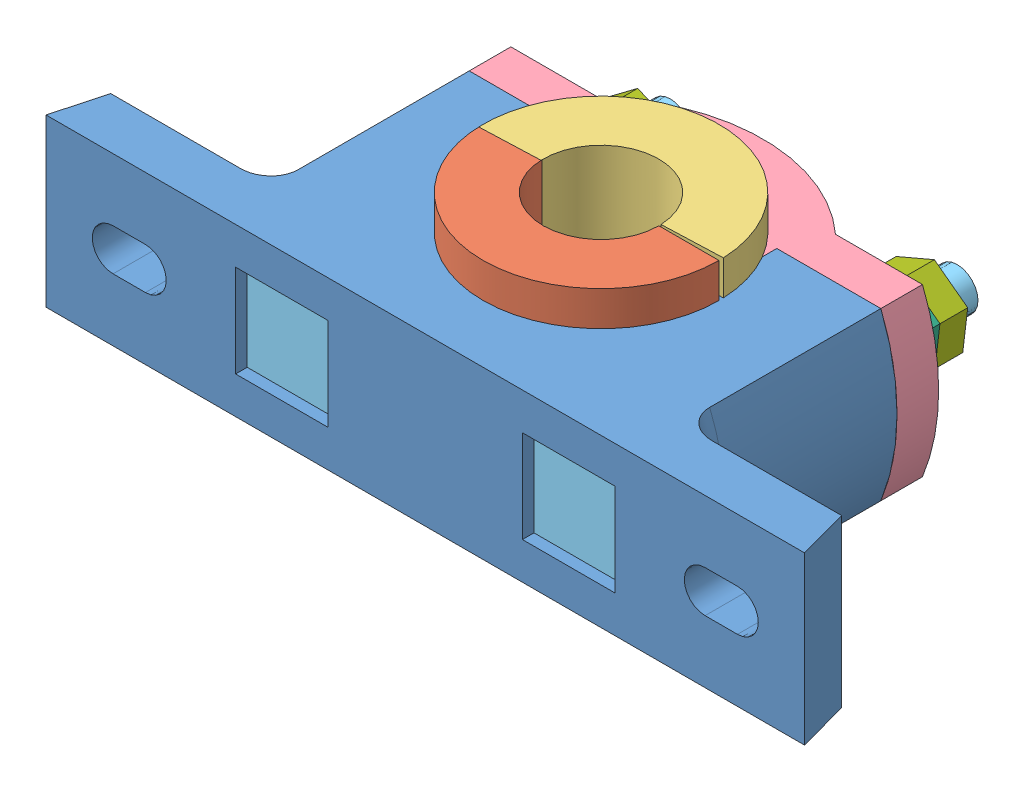
SolidWorks assembly Assem1, configuration Default. Lengths in mm.
Overall size (164 51 84).
10 component instances, 7 part files, 20 mates.
Components (placement in the parent):
- casting-1: casting [Default] at (-12.8779 141.074 -86.6135) size (164 36 54)
- brass lower-1: brass lower [Default] at (-12.8779 141.074 -124.6135) x (0 1 0) z (0 0 1) size (51 51 25.5)
- brass upper-1: brass upper [Default] at (-12.8779 141.074 -124.6135) x (0 1 0) z (-0.999278 0 0.037986) size (51 25.5 51)
- cap-1: cap [Default] at (-12.8779 141.074 -121.6135) size (96 36 32)
- bolt-1: bolt [Default] at (-43.8779 141.074 -94.6135) x (-1 0 0) z (0 0 1) size (19 19 82)
- nut-2: nut [Default] at (-43.8779 141.074 -158.6135) x (0.119049 -0.992888 0) z (0 0 1) size (18 15.59 9)
- lock nut-2: lock nut [Default] at (-43.8779 141.074 -164.6135) x (-0.800342 -0.599543 0) z (0 0 1) size (18 15.59 6)
- bolt-2: bolt [Default] at (18.1221 141.074 -94.6135) x (-1 0 0) z (0 0 1) size (19 19 82)
- lock nut-3: lock nut [Default] at (18.1221 141.074 -158.6135) x (0.800342 -0.599543 0) z (0 0 -1) size (18 15.59 6)
- nut-3: nut [Default] at (18.1221 141.074 -149.6135) x (-0.119049 -0.992888 0) z (0 0 -1) size (18 15.59 9)
Mates (geometry in assembly coordinates):
- Coincident2: coincident anti-aligned: cylinder of casting-1 through (-12.8779 141.074 -105.6135) axis (0 0 -1) radius 3; circle of brass lower-1
- Parallel1: parallel aligned: plane of casting-1 through (-12.8779 159.074 -124.6135) normal (0 1 0); plane of brass lower-1 through (-12.8779 166.574 -124.6135) normal (0 1 0)
- Concentric1: concentric aligned: cylinder of brass lower-1 through (-12.8779 115.574 -124.6135) axis (0 1 0) radius 12.5; cylinder of brass upper-1 through (-12.8779 115.574 -124.6135) axis (0 1 0) radius 12.5
- Concentric2: concentric aligned: cylinder of brass lower-1 through (-12.8779 115.574 -124.6135) axis (0 1 0) radius 12.5; cylinder of brass upper-1 through (-12.8779 115.574 -124.6135) axis (0 1 0) radius 12.5
- Coincident4: coincident aligned: plane of brass lower-1 through (-12.8779 166.574 -124.6135) normal (0 1 0); plane of brass upper-1 through (-12.8779 166.574 -124.6135) normal (0 1 0)
- Coincident5: coincident anti-aligned: circle of casting-1; cylinder of cap-1 through (18.1221 141.074 -127.6135) axis (0 0 -1) radius 4.5
- Coincident6: coincident anti-aligned: plane of casting-1 through (37.1221 159.074 -140.6135) normal (0 0 -1); plane of cap-1 through (9.1221 159.074 -140.6135) normal (0 0 1)
- Concentric4: concentric aligned: cylinder of casting-1 through (-43.8779 141.074 -140.6135) axis (0 0 1) radius 4.5; cylinder of bolt-1 through (-43.8779 141.074 -170.6135) axis (0 0 1) radius 4.5
- Parallel3: parallel aligned: plane of casting-1 through (-33.8779 151.074 -94.6135) normal (-1 0 0); plane of bolt-1 through (-53.3779 150.574 -88.6135) normal (-1 0 0)
- Parallel5: parallel aligned: plane of casting-1 through (-53.8779 151.074 -94.6135) normal (1 0 0); plane of bolt-1 through (-34.3779 150.574 -88.6135) normal (1 0 0)
- Coincident11: coincident anti-aligned: plane of casting-1 through (-12.8779 141.074 -94.6135) normal (0 0 1); plane of bolt-1 through (-43.8779 141.074 -94.6135) normal (0 0 -1)
- Coincident26: coincident anti-aligned: line of casting-1 through (-34.8779 123.074 -140.6135) axis (-1 0 0); line of cap-1 through (-57.3751 123.074 -140.6135) axis (1 0 0)
- Concentric7: concentric anti-aligned: cylinder of bolt-1 through (-43.8779 141.074 -170.6135) axis (0 0 1) radius 4.5; cylinder of nut-2 through (-43.8779 141.074 -149.6135) axis (0 0 -1) radius 4.5
- Coincident30: coincident anti-aligned: plane of cap-1 through (-62.8779 159.074 -149.6135) normal (0 0 -1); plane of nut-2 through (-43.8779 141.074 -149.6135) normal (0 0 1)
- Coincident34: coincident anti-aligned: plane of nut-2 through (-43.8779 141.074 -158.6135) normal (0 0 -1); plane of lock nut-2 through (-43.8779 141.074 -158.6135) normal (0 0 1)
- Concentric12: concentric anti-aligned: cylinder of bolt-1 through (-43.8779 141.074 -170.6135) axis (0 0 1) radius 4.5; cylinder of lock nut-2 through (-43.8779 141.074 -158.6135) axis (0 0 -1) radius 4.5
- Parallel15: parallel aligned: plane of brass lower-1 through (-12.8779 115.574 -124.6135) normal (0 -1 0); plane of brass upper-1 through (-12.8779 115.574 -124.6135) normal (0 -1 0)
- Parallel16: parallel aligned: plane of nut-2 through (-36.6748 146.4699 -149.6135) normal (0.393345 0.919391 0); plane of lock nut-2 through (-36.6748 146.4699 -158.6135) normal (0.393345 0.919391 0)
- Lock2: lock: unknown of brass lower-1; unknown of brass upper-1
- Concentric14: concentric aligned: cylinder of casting-1 through (-12.8779 159.074 -124.6135) axis (0 -1 0) radius 19; cylinder of brass lower-1 through (-12.8779 112.2001 -124.6135) axis (0 -1 0) radius 17.5
